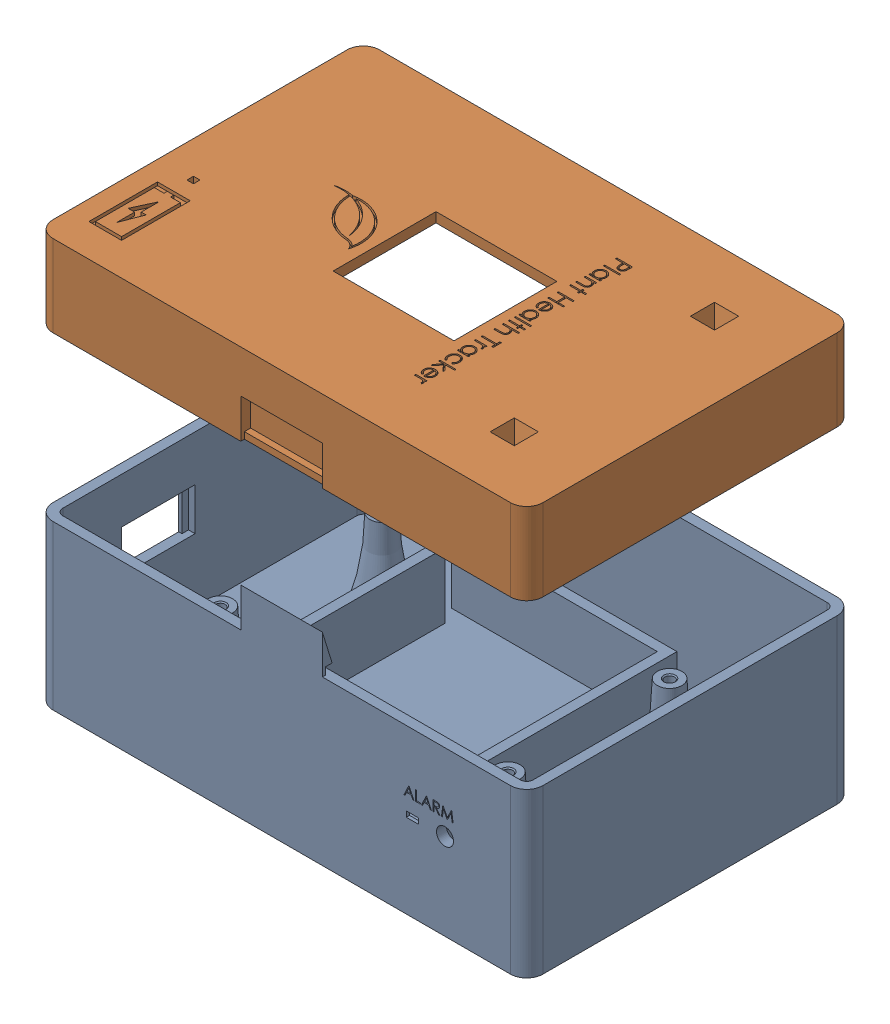
SolidWorks assembly FinalAssembly, configuration Default. Lengths in mm.
Overall size (150 125 100).
2 component instances, 2 part files, 4 mates.
Components (placement in the parent):
- Bottom-1: Bottom [Default] at (-24.4861 -22.3734 6.075) size (150 61.9 100)
- Top-1: Top [Default] at (-24.4861 102.6266 6.075) x (1 0 0) z (0 0 -1) size (150 25 100)
Mates (geometry in assembly coordinates):
- Parallel1: parallel anti-aligned: plane of Bottom-1 through (-24.4861 27.6266 6.075) normal (0 1 0); plane of Top-1 through (-24.4861 77.6266 6.075) normal (0 -1 0)
- Coincident1: coincident aligned: plane of Bottom-1 through (50.5139 27.6266 56.075) normal (1 0 0); plane of Top-1 through (50.5139 77.6266 -43.925) normal (1 0 0)
- Coincident2: coincident aligned: plane of Bottom-1 through (-99.4861 27.6266 -43.925) normal (0 0 -1); plane of Top-1 through (-99.4861 77.6266 -43.925) normal (0 0 -1)
- LimitDistance1: limit distance = 50 mm anti-aligned: plane of Top-1 through (-24.4861 77.6266 6.075) normal (0 -1 0); plane of Bottom-1 through (-24.4861 27.6266 6.075) normal (0 1 0)
